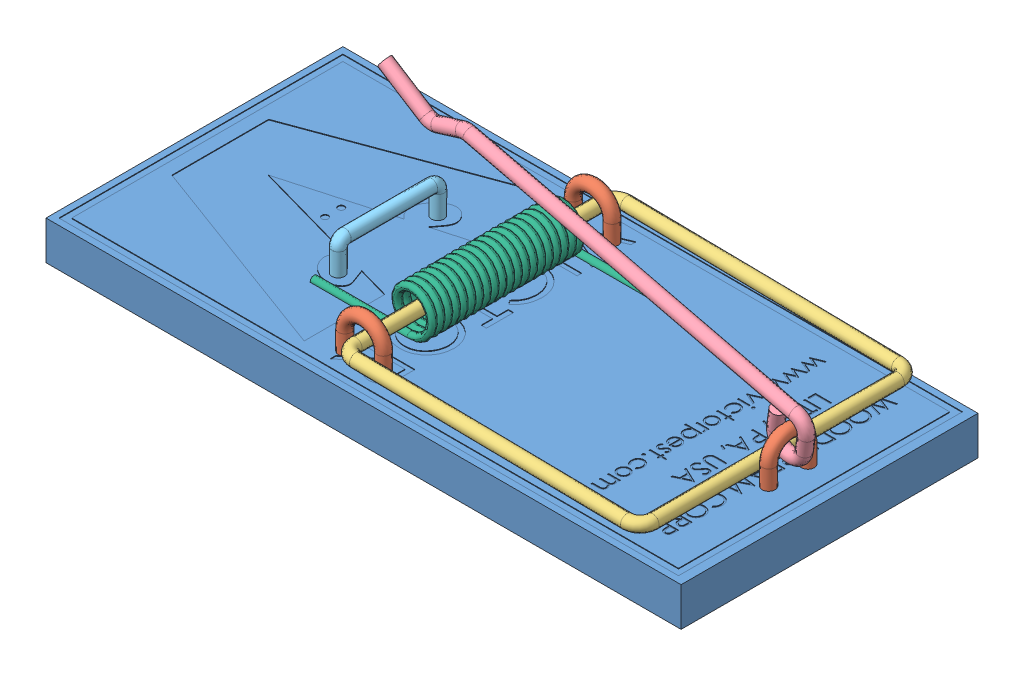
SolidWorks assembly Trappe ├á souris, configuration Défaut. Lengths in mm.
Overall size (98.4 31.43 46).
9 component instances, 7 part files, 18 mates.
Components (placement in the parent):
- Plaque de base-1: Plaque de base [Défaut] at origin size (98.4 6 46)
- Attache en U-1: Attache en U [Défaut] at (44 6 -5.3) x (-1 0 0) z (0 0 -1) size (8 7 2)
- Attache en U-2: Attache en U [Défaut] at (44 6 -40.7) x (-1 0 0) z (0 0 -1) size (8 7 2)
- Attache en U-3: Attache en U [Défaut] at (92 6 -23) x (-0.013039 0 0.999915) z (-0.999915 0 -0.013039) size (8 7 2)
- Trappe-1: Trappe [Défaut] at (66.9975 8.6612 -23) x (0 0 1) z (0.014732 0.999891 0) size (44 48 2)
- Crochet-1: Crochet [Défaut] at (90.9218 14.6527 -22.4853) x (0.974989 -0.221958 0.011473) z (-0.033791 -0.097015 0.994709) size (69.37 8.9 2)
- Attache large-1: Attache large [Défaut] at (30 6 -30.7) x (0 0 1) z (-1 0 0) size (17.4 5.5 2)
- Déclancheur-1: Déclancheur [Défaut] at (12.9656 10.0111 -28.5) x (0.996678 0.081438 0) z (0 0 1) (suppressed, hidden)
- Ressort-1: Ressort [Défaut] at (44 9 -36.518) x (0 0 1) z (-0.001663 0.999999 0) size (25.2 40.12 9.19)
Mates (geometry in assembly coordinates):
- Coïncidente1: coincident: plane of Plaque de base-1 through (0 6 0) normal (0 1 0); plane of Attache en U-1 through (41 6 -5.3) normal (0 -1 0)
- Distance1: distance = 44 mm: point of Attache en U-1; plane of Plaque de base-1 through (0 6 0) normal (-1 0 0)
- Distance2: distance = 5.3 mm: point of Attache en U-1; plane of Plaque de base-1 through (0 6 0) normal (0 0 1)
- Coïncidente5: coincident: plane of Plaque de base-1 through (0 6 0) normal (0 1 0); plane of Attache en U-2 through (41 6 -40.7) normal (0 -1 0)
- Distance3: distance = 5.3 mm: point of Attache en U-2; plane of Plaque de base-1 through (0 6 -46) normal (0 0 -1)
- Distance4: distance = 44 mm: point of Attache en U-2; plane of Plaque de base-1 through (0 6 0) normal (-1 0 0)
- Coïncidente10: coincident: plane of Plaque de base-1 through (0 6 0) normal (0 1 0); plane of Attache en U-3 through (92.0391 6 -25.9997) normal (0 -1 0)
- Distance5: distance = 6.4 mm: point of Attache en U-3; plane of Plaque de base-1 through (98.4 6 0) normal (1 0 0)
- Distance6: distance = 23 mm: plane of Plaque de base-1 through (0 6 0) normal (0 0 1); point of Attache en U-3
- Coaxiale2: concentric: circle of Attache en U-1; cylinder of Trappe-1 through (44 9 -4) axis (0 0 -1) radius 1
- Coaxiale3: concentric: circle of Attache en U-2; cylinder of Trappe-1 through (44 9 -4) axis (0 0 -1) radius 1
- Coïncidente12: coincident: point of Attache en U-3; point of Crochet-1
- Coïncidente13: coincident: plane of Plaque de base-1 through (0 6 0) normal (0 1 0); plane of Attache large-1 through (30 6 -30.7) normal (0 -1 0)
- Coaxiale5: concentric: cylinder of Attache large-1 through (30 10.5 -29.7) axis (0 0 1) radius 1; cylinder of Déclancheur-1 through (30 10.5 -17.5) axis (0 0 -1) radius 1.4
- Distance12: distance = 30 mm: point of Attache large-1; line of Plaque de base-1 through (0 6 0) axis (0 0 -1)
- Distance14: distance = 15.3 mm: line of Plaque de base-1 through (98.4 0 6) axis (0 1 0); point of Attache large-1
- Distance15: distance = 17.5 mm: plane of Déclancheur-1 through (30.8453 9.384 -17.5) normal (0 0 1); plane of Plaque de base-1 through (0 6 0) normal (0 0 1)
- Coaxiale7: concentric: axis of Trappe-1 through (44 9 -4) axis (0 0 -1); circle of Ressort-1
